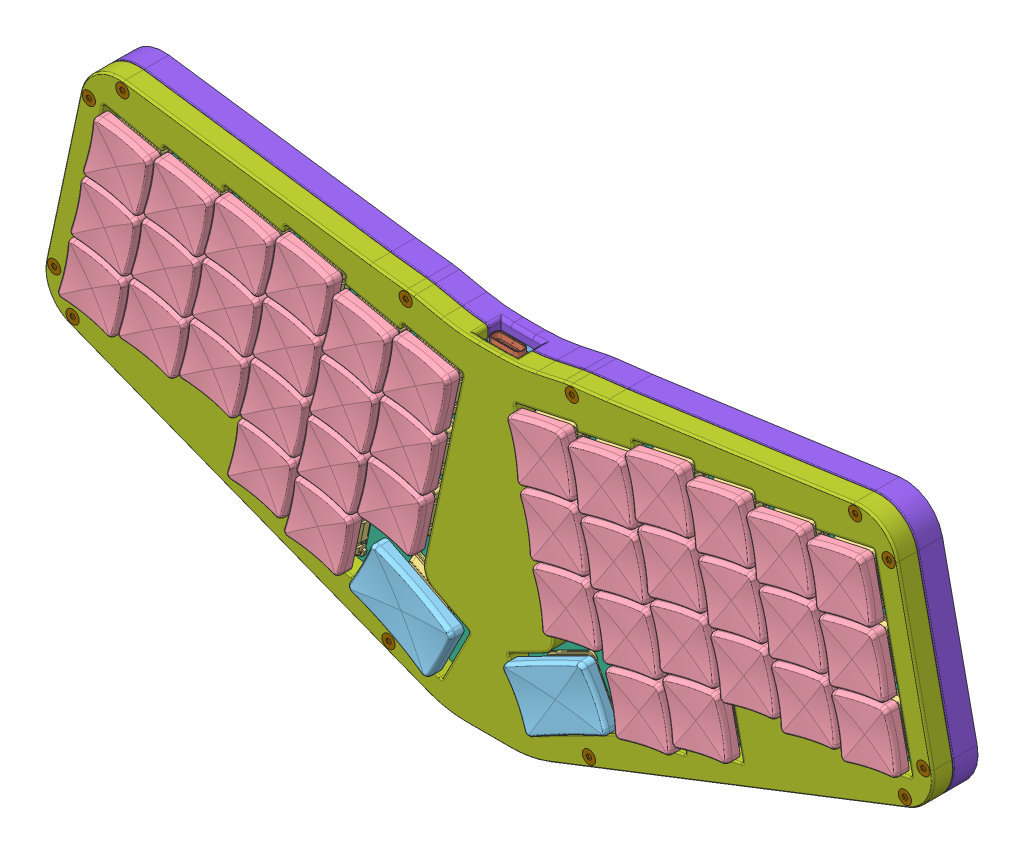
SolidWorks assembly thingamaboard, configuration Default. Lengths in mm.
Overall size (254.87 110.42 17.82).
102 component instances, 9 part files, 35 mates.
Components (placement in the parent):
- pcb-1: pcb [Default] at (-93.0137 -337.379 141.7643) size (242.52 98.19 15.02)
  - pcb_base-1: pcb_base [Default] at (-103.1831 232.8514 177.6164) size (242.52 98.19 4.48)
  - usb_c_connector-2: usb_c_connector [Default] at (101.2969 172.9514 179.2464) x (-1 0 0) z (0 0 1) size (8.95 7.9 4.2)
  - kailh_choc_switch-1: kailh_choc_switch [Default] at (-6.8998 168.7135 181.3922) x (0.978148 -0.207912 0) z (0 0 1) size (15 15 11)
  - kailh_choc_switch-2: kailh_choc_switch [Default] at (-10.4862 151.8404 181.3922) x (0.978148 -0.207912 0) z (0 0 1) size (15 15 11)
  - kailh_choc_switch-3: kailh_choc_switch [Default] at (10.3891 167.0833 181.3922) x (0.978148 -0.207912 0) z (0 0 1) size (15 15 11)
  - kailh_choc_switch-4: kailh_choc_switch [Default] at (6.8026 150.2102 181.3922) x (0.978148 -0.207912 0) z (0 0 1) size (15 15 11)
  - kailh_choc_switch-5: kailh_choc_switch [Default] at (-14.0727 134.9674 181.3922) x (0.978148 -0.207912 0) z (0 0 1) size (15 15 11)
  - kailh_choc_switch-6: kailh_choc_switch [Default] at (3.2162 133.3372 181.3922) x (0.978148 -0.207912 0) z (0 0 1) size (15 15 11)
  - kailh_choc_switch-7: kailh_choc_switch [Default] at (27.7819 165.9422 181.3922) x (0.978148 -0.207912 0) z (0 0 1) size (15 15 11)
  - kailh_choc_switch-8: kailh_choc_switch [Default] at (24.1955 149.0691 181.3922) x (0.978148 -0.207912 0) z (0 0 1) size (15 15 11)
  - kailh_choc_switch-9: kailh_choc_switch [Default] at (20.609 132.1961 181.3922) x (0.978148 -0.207912 0) z (0 0 1) size (15 15 11)
  - kailh_choc_switch-10: kailh_choc_switch [Default] at (34.4153 114.1819 181.3922) x (0.978148 -0.207912 0) z (0 0 1) size (15 15 11)
  - kailh_choc_switch-11: kailh_choc_switch [Default] at (38.0018 131.055 181.3922) x (0.978148 -0.207912 0) z (0 0 1) size (15 15 11)
  - kailh_choc_switch-12: kailh_choc_switch [Default] at (41.5883 147.928 181.3922) x (0.978148 -0.207912 0) z (0 0 1) size (15 15 11)
  - kailh_choc_switch-13: kailh_choc_switch [Default] at (45.1748 164.8011 181.3922) x (0.978148 -0.207912 0) z (0 0 1) size (15 15 11)
  - kailh_choc_switch-14: kailh_choc_switch [Default] at (50.7686 108.1501 181.3922) x (0.978148 -0.207912 0) z (0 0 1) size (15 15 11)
  - kailh_choc_switch-15: kailh_choc_switch [Default] at (54.3551 125.0231 181.3922) x (0.978148 -0.207912 0) z (0 0 1) size (15 15 11)
  - kailh_choc_switch-16: kailh_choc_switch [Default] at (57.9415 141.8962 181.3922) x (0.978148 -0.207912 0) z (0 0 1) size (15 15 11)
  - kailh_choc_switch-17: kailh_choc_switch [Default] at (61.528 158.7692 181.3922) x (0.978148 -0.207912 0) z (0 0 1) size (15 15 11)
  - kailh_choc_switch-18: kailh_choc_switch [Default] at (78.8169 157.139 181.3922) x (0.978148 -0.207912 0) z (0 0 1) size (15 15 11)
  - kailh_choc_switch-19: kailh_choc_switch [Default] at (75.2304 140.266 181.3922) x (0.978148 -0.207912 0) z (0 0 1) size (15 15 11)
  - kailh_choc_switch-20: kailh_choc_switch [Default] at (71.6439 123.3929 181.3922) x (0.978148 -0.207912 0) z (0 0 1) size (15 15 11)
  - kailh_choc_switch-21: kailh_choc_switch [Default] at (74.6872 99.2323 181.3922) x (0.891007 -0.45399 0) z (0 0 1) size (15 15 11)
  - kailh_choc_switch-22: kailh_choc_switch [Default] at (118.9466 99.2323 181.3922) x (0.891007 0.45399 0) z (0 0 1) size (15 15 11)
  - kailh_choc_switch-23: kailh_choc_switch [Default] at (121.9898 123.3929 181.3922) x (0.978148 0.207912 0) z (0 0 1) size (15 15 11)
  - kailh_choc_switch-24: kailh_choc_switch [Default] at (118.4034 140.266 181.3922) x (0.978148 0.207912 0) z (0 0 1) size (15 15 11)
  - kailh_choc_switch-25: kailh_choc_switch [Default] at (114.8169 157.139 181.3922) x (0.978148 0.207912 0) z (0 0 1) size (15 15 11)
  - kailh_choc_switch-26: kailh_choc_switch [Default] at (142.8652 108.1501 181.3922) x (0.978148 0.207912 0) z (0 0 1) size (15 15 11)
  - kailh_choc_switch-27: kailh_choc_switch [Default] at (139.2787 125.0231 181.3922) x (0.978148 0.207912 0) z (0 0 1) size (15 15 11)
  - kailh_choc_switch-28: kailh_choc_switch [Default] at (135.6922 141.8962 181.3922) x (0.978148 0.207912 0) z (0 0 1) size (15 15 11)
  - kailh_choc_switch-29: kailh_choc_switch [Default] at (132.1058 158.7692 181.3922) x (0.978148 0.207912 0) z (0 0 1) size (15 15 11)
  - kailh_choc_switch-30: kailh_choc_switch [Default] at (159.2185 114.1819 181.3922) x (0.978148 0.207912 0) z (0 0 1) size (15 15 11)
  - kailh_choc_switch-31: kailh_choc_switch [Default] at (155.632 131.055 181.3922) x (0.978148 0.207912 0) z (0 0 1) size (15 15 11)
  - kailh_choc_switch-32: kailh_choc_switch [Default] at (152.0455 147.928 181.3922) x (0.978148 0.207912 0) z (0 0 1) size (15 15 11)
  - kailh_choc_switch-33: kailh_choc_switch [Default] at (148.459 164.8011 181.3922) x (0.978148 0.207912 0) z (0 0 1) size (15 15 11)
  - kailh_choc_switch-34: kailh_choc_switch [Default] at (173.0248 132.1961 181.3922) x (0.978148 0.207912 0) z (0 0 1) size (15 15 11)
  - kailh_choc_switch-35: kailh_choc_switch [Default] at (169.4383 149.0691 181.3922) x (0.978148 0.207912 0) z (0 0 1) size (15 15 11)
  - kailh_choc_switch-36: kailh_choc_switch [Default] at (165.8519 165.9422 181.3922) x (0.978148 0.207912 0) z (0 0 1) size (15 15 11)
  - kailh_choc_switch-37: kailh_choc_switch [Default] at (190.4176 133.3372 181.3922) x (0.978148 0.207912 0) z (0 0 1) size (15 15 11)
  - kailh_choc_switch-38: kailh_choc_switch [Default] at (186.8312 150.2102 181.3922) x (0.978148 0.207912 0) z (0 0 1) size (15 15 11)
  - kailh_choc_switch-39: kailh_choc_switch [Default] at (183.2447 167.0833 181.3922) x (0.978148 0.207912 0) z (0 0 1) size (15 15 11)
  - kailh_choc_switch-40: kailh_choc_switch [Default] at (207.7065 134.9674 181.3922) x (0.978148 0.207912 0) z (0 0 1) size (15 15 11)
  - kailh_choc_switch-41: kailh_choc_switch [Default] at (204.12 151.8404 181.3922) x (0.978148 0.207912 0) z (0 0 1) size (15 15 11)
  - kailh_choc_switch-42: kailh_choc_switch [Default] at (200.5336 168.7135 181.3922) x (0.978148 0.207912 0) z (0 0 1) size (15 15 11)
  - 1U-keycap-1: 1U-keycap [Default] at (-16.6848 162.359 186.1922) x (0.978148 -0.207912 0) z (-0.207912 -0.978148 0) size (16.7 6.52 16.7)
  - 1U-keycap-2: 1U-keycap [Default] at (-20.2712 145.486 186.1922) x (0.978148 -0.207912 0) z (-0.207912 -0.978148 0) size (16.7 6.52 16.7)
  - 1U-keycap-3: 1U-keycap [Default] at (-23.8577 128.6129 186.1922) x (0.978148 -0.207912 0) z (-0.207912 -0.978148 0) size (16.7 6.52 16.7)
  - 1U-keycap-4: 1U-keycap [Default] at (0.6041 160.7288 186.1922) x (0.978148 -0.207912 0) z (-0.207912 -0.978148 0) size (16.7 6.52 16.7)
  - 1.5U-keycap-1: 1.5U-keycap [Default] at (59.3586 97.7833 186.1922) x (0.891007 -0.45399 0) z (-0.45399 -0.891007 0) size (26.46 7.52 16.96)
  - 1U-keycap-5: 1U-keycap [Default] at (40.9836 101.7956 186.1922) x (0.978148 -0.207912 0) z (-0.207912 -0.978148 0) size (16.7 6.52 16.7)
  - 1U-keycap-6: 1U-keycap [Default] at (24.6303 107.8275 186.1922) x (0.978148 -0.207912 0) z (-0.207912 -0.978148 0) size (16.7 6.52 16.7)
  - 1U-keycap-7: 1U-keycap [Default] at (44.5701 118.6687 186.1922) x (0.978148 -0.207912 0) z (-0.207912 -0.978148 0) size (16.7 6.52 16.7)
  - 1U-keycap-8: 1U-keycap [Default] at (61.859 117.0385 186.1922) x (0.978148 -0.207912 0) z (-0.207912 -0.978148 0) size (16.7 6.52 16.7)
  - 1U-keycap-9: 1U-keycap [Default] at (69.0319 150.7846 186.1922) x (0.978148 -0.207912 0) z (-0.207912 -0.978148 0) size (16.7 6.52 16.7)
  - 1U-keycap-10: 1U-keycap [Default] at (31.8033 141.5736 186.1922) x (0.978148 -0.207912 0) z (-0.207912 -0.978148 0) size (16.7 6.52 16.7)
  - 1.5U-keycap-2: 1.5U-keycap [Default] at (111.109 85.9796 186.1922) x (0.891007 0.45399 0) z (0.45399 -0.891007 0) size (26.46 7.52 16.96)
  - 1U-keycap-11: 1U-keycap [Default] at (136.5107 98.3651 186.1922) x (0.978148 0.207912 0) z (0.207912 -0.978148 0) size (16.7 6.52 16.7)
  - 1U-keycap-14: 1U-keycap [Default] at (108.4624 147.3541 186.1922) x (0.978148 0.207912 0) z (0.207912 -0.978148 0) size (16.7 6.52 16.7)
  - 1U-keycap-15: 1U-keycap [Default] at (194.1791 158.9285 186.1922) x (0.978148 0.207912 0) z (0.207912 -0.978148 0) size (16.7 6.52 16.7)
  - 1U-keycap-16: 1U-keycap [Default] at (201.3521 125.1824 186.1922) x (0.978148 0.207912 0) z (0.207912 -0.978148 0) size (16.7 6.52 16.7)
  - 1U-keycap-17: 1U-keycap [Default] at (166.6704 122.4111 186.1922) x (0.978148 0.207912 0) z (0.207912 -0.978148 0) size (16.7 6.52 16.7)
  - 1U-keycap-18: 1U-keycap [Default] at (-2.9824 143.8558 186.1922) x (0.978148 -0.207912 0) z (-0.207912 -0.978148 0) size (16.7 6.52 16.7)
  - 1U-keycap-19: 1U-keycap [Default] at (-6.5688 126.9827 186.1922) x (0.978148 -0.207912 0) z (-0.207912 -0.978148 0) size (16.7 6.52 16.7)
  - 1U-keycap-20: 1U-keycap [Default] at (17.9969 159.5877 186.1922) x (0.978148 -0.207912 0) z (-0.207912 -0.978148 0) size (16.7 6.52 16.7)
  - 1U-keycap-21: 1U-keycap [Default] at (14.4105 142.7147 186.1922) x (0.978148 -0.207912 0) z (-0.207912 -0.978148 0) size (16.7 6.52 16.7)
  - 1U-keycap-22: 1U-keycap [Default] at (10.824 125.8416 186.1922) x (0.978148 -0.207912 0) z (-0.207912 -0.978148 0) size (16.7 6.52 16.7)
  - 1U-keycap-23: 1U-keycap [Default] at (28.2168 124.7005 186.1922) x (0.978148 -0.207912 0) z (-0.207912 -0.978148 0) size (16.7 6.52 16.7)
  - 1U-keycap-24: 1U-keycap [Default] at (35.3898 158.4466 186.1922) x (0.978148 -0.207912 0) z (-0.207912 -0.978148 0) size (16.7 6.52 16.7)
  - 1U-keycap-25: 1U-keycap [Default] at (51.743 152.4148 186.1922) x (0.978148 -0.207912 0) z (-0.207912 -0.978148 0) size (16.7 6.52 16.7)
  - 1U-keycap-26: 1U-keycap [Default] at (48.1566 135.5417 186.1922) x (0.978148 -0.207912 0) z (-0.207912 -0.978148 0) size (16.7 6.52 16.7)
  - 1U-keycap-27: 1U-keycap [Default] at (65.4454 133.9115 186.1922) x (0.978148 -0.207912 0) z (-0.207912 -0.978148 0) size (16.7 6.52 16.7)
  - 1U-keycap-28: 1U-keycap [Default] at (112.0489 130.481 186.1922) x (0.978148 0.207912 0) z (0.207912 -0.978148 0) size (16.7 6.52 16.7)
  - 1U-keycap-29: 1U-keycap [Default] at (115.6354 113.608 186.1922) x (0.978148 0.207912 0) z (0.207912 -0.978148 0) size (16.7 6.52 16.7)
  - 1U-keycap-30: 1U-keycap [Default] at (125.7513 148.9842 186.1922) x (0.978148 0.207912 0) z (0.207912 -0.978148 0) size (16.7 6.52 16.7)
  - 1U-keycap-31: 1U-keycap [Default] at (129.3378 132.1112 186.1922) x (0.978148 0.207912 0) z (0.207912 -0.978148 0) size (16.7 6.52 16.7)
  - 1U-keycap-32: 1U-keycap [Default] at (132.9243 115.2381 186.1922) x (0.978148 0.207912 0) z (0.207912 -0.978148 0) size (16.7 6.52 16.7)
  - 1U-keycap-33: 1U-keycap [Default] at (142.1046 155.0161 186.1922) x (0.978148 0.207912 0) z (0.207912 -0.978148 0) size (16.7 6.52 16.7)
  - 1U-keycap-34: 1U-keycap [Default] at (145.6911 138.143 186.1922) x (0.978148 0.207912 0) z (0.207912 -0.978148 0) size (16.7 6.52 16.7)
  - 1U-keycap-35: 1U-keycap [Default] at (149.2775 121.27 186.1922) x (0.978148 0.207912 0) z (0.207912 -0.978148 0) size (16.7 6.52 16.7)
  - 1U-keycap-36: 1U-keycap [Default] at (152.864 104.3969 186.1922) x (0.978148 0.207912 0) z (0.207912 -0.978148 0) size (16.7 6.52 16.7)
  - 1U-keycap-37: 1U-keycap [Default] at (159.4974 156.1572 186.1922) x (0.978148 0.207912 0) z (0.207912 -0.978148 0) size (16.7 6.52 16.7)
  - 1U-keycap-38: 1U-keycap [Default] at (163.0839 139.2841 186.1922) x (0.978148 0.207912 0) z (0.207912 -0.978148 0) size (16.7 6.52 16.7)
  - 1U-keycap-39: 1U-keycap [Default] at (184.0632 123.5522 186.1922) x (0.978148 0.207912 0) z (0.207912 -0.978148 0) size (16.7 6.52 16.7)
  - 1U-keycap-40: 1U-keycap [Default] at (180.4767 140.4252 186.1922) x (0.978148 0.207912 0) z (0.207912 -0.978148 0) size (16.7 6.52 16.7)
  - 1U-keycap-41: 1U-keycap [Default] at (176.8902 157.2983 186.1922) x (0.978148 0.207912 0) z (0.207912 -0.978148 0) size (16.7 6.52 16.7)
  - 1U-keycap-42: 1U-keycap [Default] at (197.7656 142.0554 186.1922) x (0.978148 0.207912 0) z (0.207912 -0.978148 0) size (16.7 6.52 16.7)
- plate-3: plate [Default] at (-110.6729 -219.2847 321.9564) size (244.52 101.2 1.2)
- new_top_piece-1: new_top_piece [Default] at (-110.6729 -219.2847 323.1564) x (1 0 0) z (0 -1 0) size (254.87 6.01 110.42)
- bottom_piece-1: bottom_piece [Default] at (-110.6729 -219.2847 315.1564) x (1 0 0) z (0 -1 0) size (254.72 7 110.4)
- M2_screws-1: M2_screws [Default] at (-24.9386 -250.5759 328.1564) x (1 0 0) z (0 1 0) size (3.8 10.5 3.8)
- M2_screws-2: M2_screws [Default] at (-115.5801 -215.2514 328.1564) x (1 0 0) z (0 1 0) size (3.8 10.5 3.8)
- M2_screws-3: M2_screws [Default] at (-120.8694 -205.4504 328.1564) x (-1 0 0) z (0 -1 0) size (3.8 10.5 3.8)
- M2_screws-4: M2_screws [Default] at (-110.9197 -158.6407 328.1564) x (1 0 0) z (0 1 0) size (3.8 10.5 3.8)
- M2_screws-5: M2_screws [Default] at (-101.3107 -151.9124 328.1564) x (-1 0 0) z (0 -1 0) size (3.8 10.5 3.8)
- M2_screws-6: M2_screws [Default] at (-20.0227 -163.109 328.1564) x (1 0 0) z (0 1 0) size (3.8 10.5 3.8)
- M2_screws-7: M2_screws [Default] at (32.545 -250.5759 328.1564) x (1 0 0) z (0 1 0) size (3.8 10.5 3.8)
- M2_screws-8: M2_screws [Default] at (27.6291 -163.109 328.1564) x (1 0 0) z (0 1 0) size (3.8 10.5 3.8)
- M2_screws-9: M2_screws [Default] at (108.9171 -151.9124 328.1564) x (1 0 0) z (0 1 0) size (3.8 10.5 3.8)
- M2_screws-10: M2_screws [Default] at (118.5261 -158.6407 328.1564) x (-1 0 0) z (0 -1 0) size (3.8 10.5 3.8)
- M2_screws-11: M2_screws [Default] at (123.1865 -215.2514 328.1564) x (-1 0 0) z (0 -1 0) size (3.8 10.5 3.8)
- M2_screws-12: M2_screws [Default] at (128.4758 -205.4504 328.1564) x (1 0 0) z (0 1 0) size (3.8 10.5 3.8)
Mates (geometry in assembly coordinates):
- Coincident1: coincident anti-aligned: plane of pcb-1/kailh_choc_switch-5 through (-115.7921 -208.0652 323.1564) normal (0 0 -1); plane of plate-3 through (-110.6729 -219.2847 323.1564) normal (0 0 1)
- Concentric1: concentric anti-aligned: cylinder of pcb-1/pcb_base-1 through (3.8032 -180.8637 318.5906) axis (0 0 1) radius 1.6; cylinder of plate-3 through (3.8032 -180.8637 323.1564) axis (0 0 -1) radius 1
- Concentric2: concentric anti-aligned: cylinder of pcb-1/pcb_base-1 through (3.8032 -237.6264 318.5906) axis (0 0 1) radius 1.6; cylinder of plate-3 through (3.8032 -237.6264 323.1564) axis (0 0 -1) radius 1
- Concentric3: concentric anti-aligned: cylinder of plate-3 through (3.8032 -180.8637 323.1564) axis (0 0 -1) radius 1; cylinder of pcb-1/pcb_base-1 through (3.8032 -180.8637 318.5906) axis (0 0 1) radius 1.6
- Concentric4: concentric aligned: cylinder of plate-3 through (3.8032 -180.8637 323.1564) axis (0 0 -1) radius 1; cylinder of new_top_piece-1 through (3.8032 -180.8637 328.1564) axis (0 0 -1) radius 1
- Concentric5: concentric aligned: cylinder of plate-3 through (3.8032 -237.6264 323.1564) axis (0 0 -1) radius 1; cylinder of new_top_piece-1 through (3.8032 -237.6264 328.1564) axis (0 0 -1) radius 1
- Coincident2: coincident anti-aligned: plane of plate-3 through (-110.6729 -219.2847 323.1564) normal (0 0 1); plane of new_top_piece-1 through (-110.6729 -219.2847 323.1564) normal (0 0 -1)
- Concentric6: concentric aligned: cylinder of new_top_piece-1 through (-110.9197 -158.6407 328.1564) axis (0 0 -1) radius 1; cylinder of bottom_piece-1 through (-110.9197 -158.6407 322.1564) axis (0 0 -1) radius 1
- Concentric7: concentric aligned: cylinder of new_top_piece-1 through (128.4758 -205.4504 328.1564) axis (0 0 -1) radius 1; cylinder of bottom_piece-1 through (128.4758 -205.4504 322.1564) axis (0 0 -1) radius 1
- Coincident3: coincident anti-aligned: plane of new_top_piece-1 through (-110.6729 -219.2847 322.1564) normal (0 0 -1); plane of bottom_piece-1 through (-110.6729 -219.2847 322.1564) normal (0 0 1)
- Concentric8: concentric anti-aligned: cylinder of new_top_piece-1 through (-24.9386 -250.5759 328.1564) axis (0 0 -1) radius 1; cylinder of M2_screws-1 through (-24.9386 -250.5759 317.6564) axis (0 0 1) radius 1
- Coincident4: coincident aligned: cone of new_top_piece-1 through (-24.9386 -250.5759 327.2564) axis (0 0 -1); cone of M2_screws-1 through (-24.9386 -250.5759 327.2564) axis (0 0 -1)
- Concentric9: concentric anti-aligned: cylinder of new_top_piece-1 through (-115.5801 -215.2514 328.1564) axis (0 0 -1) radius 1; cylinder of M2_screws-2 through (-115.5801 -215.2514 317.6564) axis (0 0 1) radius 1
- Coincident5: coincident aligned: cone of new_top_piece-1 through (-115.5801 -215.2514 327.2564) axis (0 0 -1); cone of M2_screws-2 through (-115.5801 -215.2514 327.2564) axis (0 0 -1)
- Concentric10: concentric anti-aligned: cylinder of new_top_piece-1 through (-120.8694 -205.4504 328.1564) axis (0 0 -1) radius 1; cylinder of M2_screws-3 through (-120.8694 -205.4504 317.6564) axis (0 0 1) radius 1
- Coincident6: coincident aligned: cone of new_top_piece-1 through (-120.8694 -205.4504 327.2564) axis (0 0 -1); cone of M2_screws-3 through (-120.8694 -205.4504 327.2564) axis (0 0 -1)
- Concentric11: concentric anti-aligned: cylinder of new_top_piece-1 through (-110.9197 -158.6407 328.1564) axis (0 0 -1) radius 1; cylinder of M2_screws-4 through (-110.9197 -158.6407 317.6564) axis (0 0 1) radius 1
- Concentric12: concentric anti-aligned: cylinder of new_top_piece-1 through (-101.3107 -151.9124 328.1564) axis (0 0 -1) radius 1; cylinder of M2_screws-5 through (-101.3107 -151.9124 317.6564) axis (0 0 1) radius 1
- Coincident7: coincident aligned: cone of new_top_piece-1 through (-110.9197 -158.6407 327.2564) axis (0 0 -1); cone of M2_screws-4 through (-110.9197 -158.6407 327.2564) axis (0 0 -1)
- Concentric13: concentric aligned: cone of M2_screws-5 through (-101.3107 -151.9124 327.2564) axis (0 0 -1); cone of new_top_piece-1 through (-101.3107 -151.9124 327.2564) axis (0 0 -1)
- Coincident8: coincident aligned: cone of new_top_piece-1 through (-101.3107 -151.9124 327.2564) axis (0 0 -1); cone of M2_screws-5 through (-101.3107 -151.9124 327.2564) axis (0 0 -1)
- Concentric14: concentric anti-aligned: cylinder of new_top_piece-1 through (-20.0227 -163.109 328.1564) axis (0 0 -1) radius 1; cylinder of M2_screws-6 through (-20.0227 -163.109 317.6564) axis (0 0 1) radius 1
- Coincident9: coincident aligned: cone of new_top_piece-1 through (-20.0227 -163.109 327.2564) axis (0 0 -1); cone of M2_screws-6 through (-20.0227 -163.109 327.2564) axis (0 0 -1)
- Concentric15: concentric anti-aligned: cylinder of new_top_piece-1 through (27.6291 -163.109 328.1564) axis (0 0 -1) radius 1; cylinder of M2_screws-8 through (27.6291 -163.109 317.6564) axis (0 0 1) radius 1
- Coincident10: coincident aligned: cone of new_top_piece-1 through (27.6291 -163.109 327.2564) axis (0 0 -1); cone of M2_screws-8 through (27.6291 -163.109 327.2564) axis (0 0 -1)
- Concentric16: concentric anti-aligned: cylinder of new_top_piece-1 through (32.545 -250.5759 328.1564) axis (0 0 -1) radius 1; cylinder of M2_screws-7 through (32.545 -250.5759 317.6564) axis (0 0 1) radius 1
- Coincident11: coincident aligned: cone of new_top_piece-1 through (32.545 -250.5759 327.2564) axis (0 0 -1); cone of M2_screws-7 through (32.545 -250.5759 327.2564) axis (0 0 -1)
- Concentric17: concentric anti-aligned: cylinder of new_top_piece-1 through (123.1865 -215.2514 328.1564) axis (0 0 -1) radius 1; cylinder of M2_screws-11 through (123.1865 -215.2514 317.6564) axis (0 0 1) radius 1
- Coincident12: coincident aligned: cone of new_top_piece-1 through (123.1865 -215.2514 327.2564) axis (0 0 -1); cone of M2_screws-11 through (123.1865 -215.2514 327.2564) axis (0 0 -1)
- Concentric18: concentric anti-aligned: cylinder of new_top_piece-1 through (128.4758 -205.4504 328.1564) axis (0 0 -1) radius 1; cylinder of M2_screws-12 through (128.4758 -205.4504 317.6564) axis (0 0 1) radius 1
- Coincident13: coincident aligned: cone of new_top_piece-1 through (128.4758 -205.4504 327.2564) axis (0 0 -1); cone of M2_screws-12 through (128.4758 -205.4504 327.2564) axis (0 0 -1)
- Concentric19: concentric anti-aligned: cylinder of new_top_piece-1 through (118.5261 -158.6407 328.1564) axis (0 0 -1) radius 1; cylinder of M2_screws-10 through (118.5261 -158.6407 317.6564) axis (0 0 1) radius 1
- Coincident14: coincident aligned: cone of new_top_piece-1 through (118.5261 -158.6407 327.2564) axis (0 0 -1); cone of M2_screws-10 through (118.5261 -158.6407 327.2564) axis (0 0 -1)
- Concentric20: concentric anti-aligned: cylinder of new_top_piece-1 through (108.9171 -151.9124 328.1564) axis (0 0 -1) radius 1; cylinder of M2_screws-9 through (108.9171 -151.9124 317.6564) axis (0 0 1) radius 1
- Coincident15: coincident aligned: cone of new_top_piece-1 through (108.9171 -151.9124 327.2564) axis (0 0 -1); cone of M2_screws-9 through (108.9171 -151.9124 327.2564) axis (0 0 -1)
